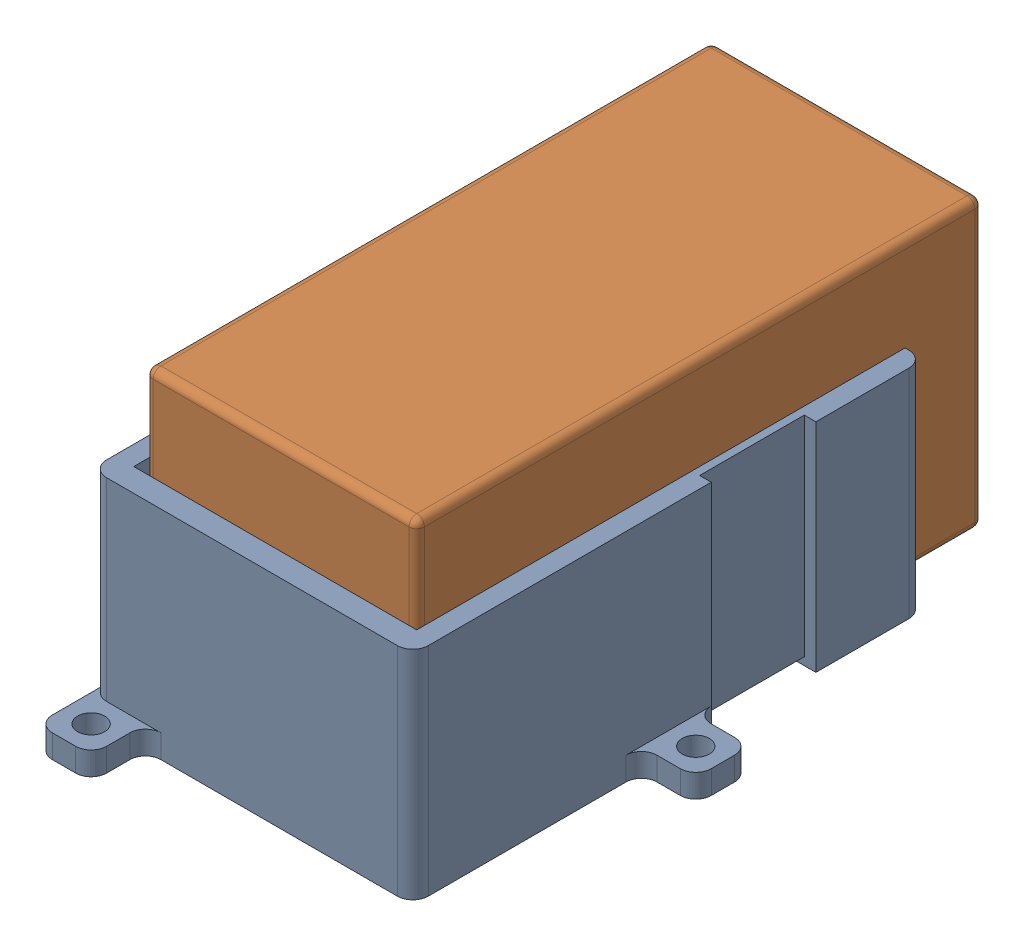
SolidWorks assembly liPoAssembly_rev5, configuration Default. Lengths in mm.
Overall size (48.5 40 85.5).
2 component instances, 2 part files, 6 mates.
Components (placement in the parent):
- liPoBatteryMount-1: liPoBatteryMount [Default] at (10.4 0 33) x (0 0 1) z (-1 0 0) size (73 28 48.5)
- liPoBattery-1: liPoBattery [Default] at (0.75 21.5 26.5) x (0 -1 0) z (0 0 1) size (37 35 75.5)
Mates (geometry in assembly coordinates):
- Coincident1: coincident anti-aligned: plane of liPoBatteryMount-1 through (10.4 0 33) normal (0 -1 0)
- Coincident3: coincident: point of liPoBatteryMount-1
- Coincident4: coincident anti-aligned: plane of liPoBatteryMount-1 through (10.4 3 33) normal (0 1 0); plane of liPoBattery-1 through (18.25 3 63) normal (0 -1 0)
- Coincident5: coincident anti-aligned: plane of liPoBatteryMount-1 through (10.4 28 63) normal (0 0 -1); plane of liPoBattery-1 through (18.25 40 63) normal (0 0 1)
- Coincident7: coincident anti-aligned: plane of liPoBatteryMount-1 through (18.25 28 33) normal (-1 0 0); plane of liPoBattery-1 through (18.25 21.5 26.5) normal (1 0 0)
- Coincident8: coincident anti-aligned: plane of liPoBatteryMount-1 through (10.4 3 0) normal (0 0 -1)
